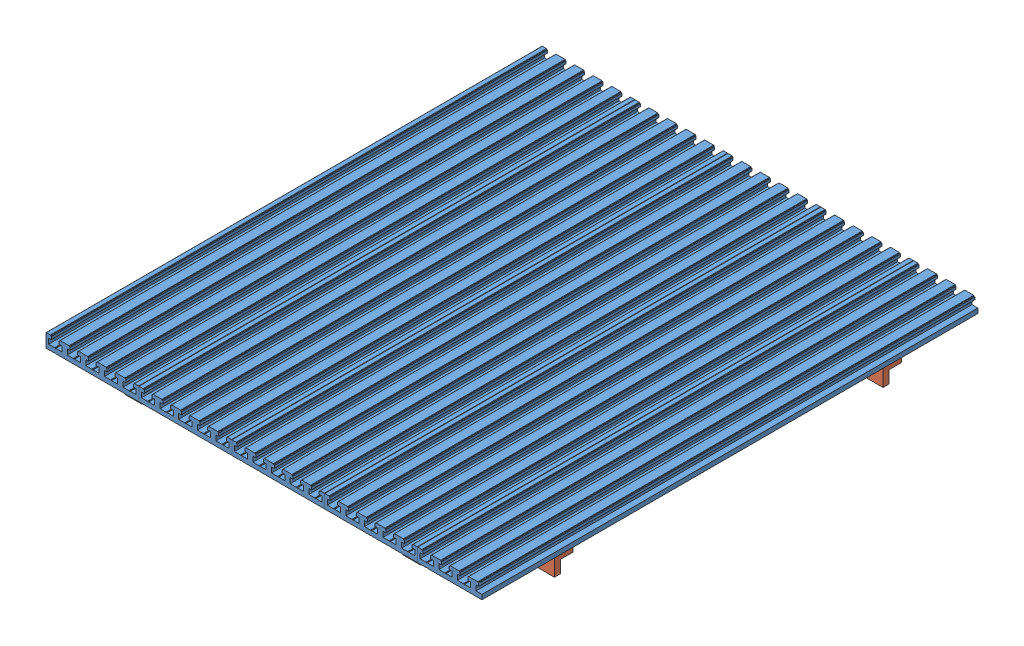
SolidWorks assembly TableTSlot, configuration Table T-Slot. Lengths in mm.
Overall size (351.6 29.5 400).
55 component instances, 6 part files, 100 mates.
Components (placement in the parent):
- T-slot Table Plate-4: T-slot Table Plate [-1 EdgeSide] at origin size (74.9 11 400)
- T-slot Table Plate-5: T-slot Table Plate [-2 Middle] at (74.9 0 0) size (74.9 11 400)
- T-slot Table Plate-6: T-slot Table Plate [-2 Middle] at (149.8 0 0) size (74.9 11 400)
- T-slot Table Plate-7: T-slot Table Plate [-1 EdgeSide] at (224.7 0 0) size (74.9 11 400)
- T-slot Table Plate-8: T-slot Table Plate [-3 aHalf] at (299.6 0 0) size (52 11 400)
- CornerBraketLong-1: CornerBraketLong [Corner Braket Long] at (312.55 -1.9 340) x (0 0 -1) z (-1 0 0) size (15 15 350)
- CornerBraketLong-2: CornerBraketLong [Corner Braket Long] at (312.55 -1.9 75) x (0 0 -1) z (-1 0 0) size (15 15 350)
- Corner Bracket 20х20L-1: Corner Bracket 20х20L [Default] at (23.5 -1.9 38.5) x (-1 0 0) z (0 0 1) size (17 18.5 18.5)
- Corner Bracket 20х20L-4: Corner Bracket 20х20L [Default] at (248.2 -1.9 38.5) x (-1 0 0) z (0 0 1) size (17 18.5 18.5)
- socket countersunk head screw_iso-1: socket countersunk head screw_iso [ISO 10642 - M3 x 16 - 16N] at (-30 1.76 65) x (0 -1 0) z (0.269005 0 -0.963139) size (16 5.54 5.54)
- socket countersunk head screw_iso-2: socket countersunk head screw_iso [ISO 10642 - M3 x 16 - 16N] at (30 1.76 65) x (0 -1 0) z (0.269005 0 -0.963139) size (16 5.54 5.54)
- socket countersunk head screw_iso-3: socket countersunk head screw_iso [ISO 10642 - M3 x 16 - 16N] at (44.9 1.76 65) x (0 -1 0) z (0.269005 0 -0.963139) size (16 5.54 5.54)
- socket countersunk head screw_iso-4: socket countersunk head screw_iso [ISO 10642 - M3 x 16 - 16N] at (104.9 1.76 65) x (0 -1 0) z (0.269005 0 -0.963139) size (16 5.54 5.54)
- socket countersunk head screw_iso-5: socket countersunk head screw_iso [ISO 10642 - M3 x 16 - 16N] at (119.8 1.76 65) x (0 -1 0) z (0.269005 0 -0.963139) size (16 5.54 5.54)
- socket countersunk head screw_iso-6: socket countersunk head screw_iso [ISO 10642 - M3 x 16 - 16N] at (179.8 1.76 65) x (0 -1 0) z (0.128637 0 -0.991692) size (16 5.54 5.54)
- socket countersunk head screw_iso-7: socket countersunk head screw_iso [ISO 10642 - M3 x 16 - 16N] at (194.7 1.76 65) x (0 -1 0) z (0.539742 0 -0.841831) size (16 5.54 5.54)
- socket countersunk head screw_iso-8: socket countersunk head screw_iso [ISO 10642 - M3 x 16 - 16N] at (254.7 1.76 65) x (0 -1 0) z (0.464702 0 -0.885467) size (16 5.54 5.54)
- socket countersunk head screw_iso-9: socket countersunk head screw_iso [ISO 10642 - M3 x 16 - 16N] at (254.7 1.76 330) x (0 -1 0) z (0.269005 0 -0.963139) size (16 5.54 5.54)
- socket countersunk head screw_iso-10: socket countersunk head screw_iso [ISO 10642 - M3 x 16 - 16N] at (194.7 1.76 330) x (0 -1 0) z (-0.059166 0 -0.998248) size (16 5.54 5.54)
- socket countersunk head screw_iso-11: socket countersunk head screw_iso [ISO 10642 - M3 x 16 - 16N] at (179.8 1.76 330) x (0 -1 0) z (0.269005 0 -0.963139) size (16 5.54 5.54)
- socket countersunk head screw_iso-12: socket countersunk head screw_iso [ISO 10642 - M3 x 16 - 16N] at (119.8 1.76 330) x (0 -1 0) z (0.269005 0 -0.963139) size (16 5.54 5.54)
- socket countersunk head screw_iso-13: socket countersunk head screw_iso [ISO 10642 - M3 x 16 - 16N] at (104.9 1.76 330) x (0 -1 0) z (0.048995 0 -0.998799) size (16 5.54 5.54)
- socket countersunk head screw_iso-14: socket countersunk head screw_iso [ISO 10642 - M3 x 16 - 16N] at (44.9 1.76 330) x (0 -1 0) z (0.269005 0 -0.963139) size (16 5.54 5.54)
- socket countersunk head screw_iso-15: socket countersunk head screw_iso [ISO 10642 - M3 x 16 - 16N] at (30 1.76 330) x (0 -1 0) z (0.351399 0 -0.936226) size (16 5.54 5.54)
- socket countersunk head screw_iso-16: socket countersunk head screw_iso [ISO 10642 - M3 x 16 - 16N] at (-30 1.76 330) x (0 -1 0) z (0.116212 0 -0.993224) size (16 5.54 5.54)
- socket head cap screw_iso-3: socket head cap screw_iso [ISO 4762 M4 x 6 - 6N] at (15 -8.4 30) x (0 1 0) z (0.250987 0 0.96799) size (10 7 7)
- socket head cap screw_iso-4: socket head cap screw_iso [ISO 4762 M4 x 6 - 6N] at (239.7 -8.4 30) x (0 1 0) z (0.250987 0 0.96799) size (10 7 7)
- Nyloc nut St_Steel A2 ISO M2_5-M36-1: Nyloc nut St_Steel A2 ISO M2_5-M36 [M3 NYLOC DIN 985] at (104.9 -6.9 65) x (0.275369 0 0.961338) z (0.961338 0 -0.275369) size (6.35 4 5.5)
- Nyloc nut St_Steel A2 ISO M2_5-M36-2: Nyloc nut St_Steel A2 ISO M2_5-M36 [M3 NYLOC DIN 985] at (119.8 -6.9 65) x (-0.786495 0 0.617596) z (0.617596 0 0.786495) size (6.35 4 5.5)
- Nyloc nut St_Steel A2 ISO M2_5-M36-3: Nyloc nut St_Steel A2 ISO M2_5-M36 [M3 NYLOC DIN 985] at (179.8 -6.9 65) x (-0.786495 0 0.617596) z (0.617596 0 0.786495) size (6.35 4 5.5)
- Nyloc nut St_Steel A2 ISO M2_5-M36-4: Nyloc nut St_Steel A2 ISO M2_5-M36 [M3 NYLOC DIN 985] at (194.7 -6.9 65) x (-0.786495 0 0.617596) z (0.617596 0 0.786495) size (6.35 4 5.5)
- Nyloc nut St_Steel A2 ISO M2_5-M36-5: Nyloc nut St_Steel A2 ISO M2_5-M36 [M3 NYLOC DIN 985] at (254.7 -6.9 65) x (-0.786495 0 0.617596) z (0.617596 0 0.786495) size (6.35 4 5.5)
- Nyloc nut St_Steel A2 ISO M2_5-M36-6: Nyloc nut St_Steel A2 ISO M2_5-M36 [M3 NYLOC DIN 985] at (44.9 -6.9 65) x (0.275369 0 0.961338) z (0.961338 0 -0.275369) size (6.35 4 5.5)
- Nyloc nut St_Steel A2 ISO M2_5-M36-7: Nyloc nut St_Steel A2 ISO M2_5-M36 [M3 NYLOC DIN 985] at (30 -6.9 65) x (0.275369 0 0.961338) z (0.961338 0 -0.275369) size (6.35 4 5.5)
- Nyloc nut St_Steel A2 ISO M2_5-M36-8: Nyloc nut St_Steel A2 ISO M2_5-M36 [M3 NYLOC DIN 985] at (-30 -6.9 65) x (0.275369 0 0.961338) z (0.961338 0 -0.275369) size (6.35 4 5.5)
- Nyloc nut St_Steel A2 ISO M2_5-M36-9: Nyloc nut St_Steel A2 ISO M2_5-M36 [M3 NYLOC DIN 985] at (-30 -6.9 330) x (0.275369 0 0.961338) z (0.961338 0 -0.275369) size (6.35 4 5.5)
- Nyloc nut St_Steel A2 ISO M2_5-M36-10: Nyloc nut St_Steel A2 ISO M2_5-M36 [M3 NYLOC DIN 985] at (30 -6.9 330) x (0.275369 0 0.961338) z (0.961338 0 -0.275369) size (6.35 4 5.5)
- Nyloc nut St_Steel A2 ISO M2_5-M36-11: Nyloc nut St_Steel A2 ISO M2_5-M36 [M3 NYLOC DIN 985] at (44.9 -6.9 330) x (0.275369 0 0.961338) z (0.961338 0 -0.275369) size (6.35 4 5.5)
- Nyloc nut St_Steel A2 ISO M2_5-M36-12: Nyloc nut St_Steel A2 ISO M2_5-M36 [M3 NYLOC DIN 985] at (104.9 -6.9 330) x (0.550614 0 0.83476) z (0.83476 0 -0.550614) size (6.35 4 5.5)
- Nyloc nut St_Steel A2 ISO M2_5-M36-13: Nyloc nut St_Steel A2 ISO M2_5-M36 [M3 NYLOC DIN 985] at (119.8 -6.9 330) x (0.275369 0 0.961338) z (0.961338 0 -0.275369) size (6.35 4 5.5)
- Nyloc nut St_Steel A2 ISO M2_5-M36-14: Nyloc nut St_Steel A2 ISO M2_5-M36 [M3 NYLOC DIN 985] at (179.8 -6.9 330) x (0.275369 0 0.961338) z (0.961338 0 -0.275369) size (6.35 4 5.5)
- Nyloc nut St_Steel A2 ISO M2_5-M36-15: Nyloc nut St_Steel A2 ISO M2_5-M36 [M3 NYLOC DIN 985] at (194.7 -6.9 330) x (0.275369 0 0.961338) z (0.961338 0 -0.275369) size (6.35 4 5.5)
- Nyloc nut St_Steel A2 ISO M2_5-M36-16: Nyloc nut St_Steel A2 ISO M2_5-M36 [M3 NYLOC DIN 985] at (254.7 -6.9 330) x (0.275369 0 0.961338) z (0.961338 0 -0.275369) size (6.35 4 5.5)
- socket countersunk head screw_iso-17: socket countersunk head screw_iso [ISO 10642 - M3 x 16 - 16N] at (269.6 1.76 330) x (0 -1 0) z (0.057721 0 -0.998333) size (16 5.54 5.54)
- socket countersunk head screw_iso-18: socket countersunk head screw_iso [ISO 10642 - M3 x 16 - 16N] at (299.6 1.76 330) x (0 -1 0) z (0.057721 0 -0.998333) size (16 5.54 5.54)
- socket countersunk head screw_iso-19: socket countersunk head screw_iso [ISO 10642 - M3 x 16 - 16N] at (269.6 1.76 65) x (0 -1 0) z (0.464702 0 -0.885467) size (16 5.54 5.54)
- socket countersunk head screw_iso-20: socket countersunk head screw_iso [ISO 10642 - M3 x 16 - 16N] at (299.6 1.76 65) x (0 -1 0) z (0.464702 0 -0.885467) size (16 5.54 5.54)
- Nyloc nut St_Steel A2 ISO M2_5-M36-17: Nyloc nut St_Steel A2 ISO M2_5-M36 [M3 NYLOC DIN 985] at (269.6 -6.9 65) x (-0.786495 0 0.617596) z (0.617596 0 0.786495) size (6.35 4 5.5)
- Nyloc nut St_Steel A2 ISO M2_5-M36-18: Nyloc nut St_Steel A2 ISO M2_5-M36 [M3 NYLOC DIN 985] at (299.6 -6.9 65) x (-0.786495 0 0.617596) z (0.617596 0 0.786495) size (6.35 4 5.5)
- Nyloc nut St_Steel A2 ISO M2_5-M36-19: Nyloc nut St_Steel A2 ISO M2_5-M36 [M3 NYLOC DIN 985] at (269.6 -6.9 330) x (0.275369 0 0.961338) z (0.961338 0 -0.275369) size (6.35 4 5.5)
- Nyloc nut St_Steel A2 ISO M2_5-M36-20: Nyloc nut St_Steel A2 ISO M2_5-M36 [M3 NYLOC DIN 985] at (299.6 -6.9 330) x (0.275369 0 0.961338) z (0.961338 0 -0.275369) size (6.35 4 5.5)
- socket head cap screw_iso-5: socket head cap screw_iso [ISO 4762 M4 x 6 - 6N] at (15 -8.4 372) x (0 1 0) z (0.500858 0 0.86553) size (10 7 7)
- socket head cap screw_iso-6: socket head cap screw_iso [ISO 4762 M4 x 6 - 6N] at (239.7 -8.4 372) x (0 1 0) z (0.500858 0 0.86553) size (10 7 7)
- Corner Bracket 20х20L-6: Corner Bracket 20х20L [Default] at (231.2 -1.9 363.5) x (1 0 0) z (0 0 -1) size (17 18.5 18.5)
- Corner Bracket 20х20L-5: Corner Bracket 20х20L [Default] at (6.5 -1.9 363.5) x (1 0 0) z (0 0 -1) size (17 18.5 18.5)
Mates (geometry in assembly coordinates):
- Coincident1: coincident aligned: plane of T-slot Table Plate-4 through (37.2 8.85 0) normal (0 0 -1); plane of T-slot Table Plate-5 through (112.1 8.85 0) normal (0 0 -1)
- Coincident2: coincident aligned: plane of T-slot Table Plate-5 through (112.1 8.85 0) normal (0 0 -1); plane of T-slot Table Plate-6 through (187 8.85 0) normal (0 0 -1)
- Coincident3: coincident aligned: plane of T-slot Table Plate-5 through (112.1 -1.9 400) normal (0 -1 0); plane of T-slot Table Plate-6 through (134.2564 -1.9 400) normal (0 -1 0)
- Coincident4: coincident aligned: plane of T-slot Table Plate-4 through (37.2 -1.9 400) normal (0 -1 0); plane of T-slot Table Plate-5 through (59.3564 -1.9 400) normal (0 -1 0)
- Coincident5: coincident anti-aligned: plane of T-slot Table Plate-4 through (37.45 8.85 400) normal (1 0 0); plane of T-slot Table Plate-5 through (37.45 -1.65 400) normal (-1 0 0)
- Coincident6: coincident anti-aligned: plane of T-slot Table Plate-5 through (112.35 8.85 400) normal (1 0 0); plane of T-slot Table Plate-6 through (112.35 -1.65 400) normal (-1 0 0)
- Coincident7: coincident aligned: plane of T-slot Table Plate-6 through (187 8.85 0) normal (0 0 -1); plane of T-slot Table Plate-7 through (261.9 8.85 0) normal (0 0 -1)
- Coincident8: coincident aligned: plane of T-slot Table Plate-6 through (187 -1.9 400) normal (0 -1 0); plane of T-slot Table Plate-7 through (194.1564 -1.9 400) normal (0 -1 0)
- Coincident9: coincident anti-aligned: plane of T-slot Table Plate-6 through (187.25 8.85 400) normal (1 0 0); plane of T-slot Table Plate-7 through (187.25 -1.65 400) normal (-1 0 0)
- Coincident10: coincident anti-aligned: plane of T-slot Table Plate-4 through (14.4564 -1.9 400) normal (0 -1 0); plane of Corner Bracket 20х20L-1 through (6.5 -1.9 24.5) normal (0 1 0)
- Coincident11: coincident anti-aligned: plane of T-slot Table Plate-4 through (-15.5436 -1.9 400) normal (0 -1 0); plane of CornerBraketLong^TableTSlot_cnc_laser_v1.0-1 through (-37.45 -1.9 325) normal (0 1 0)
- Coincident12: coincident anti-aligned: plane of T-slot Table Plate-6 through (179.2564 -1.9 400) normal (0 -1 0); plane of CornerBraketLong^TableTSlot_cnc_laser_v1.0-2 through (-37.45 -1.9 60) normal (0 1 0)
- Coincident19: coincident anti-aligned: plane of T-slot Table Plate-5 through (74.3564 -1.9 400) normal (0 -1 0); plane of Corner Bracket 20х20L-4 through (231.2 -1.9 24.5) normal (0 1 0)
- Coincident20: coincident aligned: plane of Corner Bracket 20х20L-1 through (6.5 -20.4 20) normal (0 0 -1); plane of Corner Bracket 20х20L-4 through (231.2 -20.4 20) normal (0 0 -1)
- Concentric1: concentric aligned: cylinder of socket countersunk head screw_iso-1 through (-30 1.76 65) axis (0 1 0) radius 1.5; cylinder of CornerBraketLong^TableTSlot_cnc_laser_v1.0-2 through (-30 -1.9 65) axis (0 1 0) radius 1.6
- Coincident27: coincident aligned: cone of T-slot Table Plate-4 through (-30 1.4 65) axis (0 -1 0); cylinder of socket countersunk head screw_iso-1 through (-30 1.17 65) axis (0 -1 0) radius 785.3982
- Concentric4: concentric aligned: cylinder of CornerBraketLong^TableTSlot_cnc_laser_v1.0-1 through (-30 -1.9 330) axis (0 1 0) radius 1.6; cylinder of T-slot Table Plate-4 through (-30 1.9 330) axis (0 1 0) radius 1.6
- Concentric17: concentric aligned: cylinder of socket countersunk head screw_iso-14 through (44.9 1.76 330) axis (0 1 0) radius 1.5; cylinder of CornerBraketLong^TableTSlot_cnc_laser_v1.0-1 through (44.9 -1.9 330) axis (0 1 0) radius 1.6
- Concentric18: concentric aligned: cylinder of socket countersunk head screw_iso-15 through (30 1.76 330) axis (0 1 0) radius 1.5; cylinder of CornerBraketLong^TableTSlot_cnc_laser_v1.0-1 through (30 -1.9 330) axis (0 1 0) radius 1.6
- Concentric19: concentric aligned: cylinder of socket countersunk head screw_iso-16 through (-30 1.76 330) axis (0 1 0) radius 1.5; cylinder of T-slot Table Plate-4 through (-30 1.9 330) axis (0 1 0) radius 1.6
- Coincident36: coincident aligned: cylinder of T-slot Table Plate-4 through (-30 1.4 330) axis (0 -1 0) radius 785.3982; cylinder of socket countersunk head screw_iso-16 through (-30 1.17 330) axis (0 -1 0) radius 785.3982
- Coincident37: coincident aligned: cylinder of T-slot Table Plate-4 through (30 1.4 330) axis (0 -1 0) radius 785.3982; cylinder of socket countersunk head screw_iso-15 through (30 1.17 330) axis (0 -1 0) radius 785.3982
- Coincident38: coincident aligned: cylinder of T-slot Table Plate-5 through (44.9 1.4 330) axis (0 -1 0) radius 785.3982; cylinder of socket countersunk head screw_iso-14 through (44.9 1.17 330) axis (0 -1 0) radius 785.3982
- Coincident39: coincident aligned: cylinder of T-slot Table Plate-5 through (104.9 1.4 330) axis (0 -1 0) radius 785.3982; cylinder of socket countersunk head screw_iso-13 through (104.9 1.17 330) axis (0 -1 0) radius 785.3982
- Coincident40: coincident aligned: cylinder of T-slot Table Plate-6 through (119.8 1.4 330) axis (0 -1 0) radius 785.3982; cylinder of socket countersunk head screw_iso-12 through (119.8 1.17 330) axis (0 -1 0) radius 785.3982
- Coincident41: coincident aligned: cylinder of T-slot Table Plate-6 through (179.8 1.4 330) axis (0 -1 0) radius 785.3982; cylinder of socket countersunk head screw_iso-11 through (179.8 1.17 330) axis (0 -1 0) radius 785.3982
- Coincident42: coincident aligned: cylinder of T-slot Table Plate-7 through (194.7 1.4 330) axis (0 -1 0) radius 785.3982; cylinder of socket countersunk head screw_iso-10 through (194.7 1.17 330) axis (0 -1 0) radius 785.3982
- Coincident43: coincident aligned: cylinder of T-slot Table Plate-7 through (254.7 1.4 330) axis (0 -1 0) radius 785.3982; cylinder of socket countersunk head screw_iso-9 through (254.7 1.17 330) axis (0 -1 0) radius 785.3982
- Concentric30: concentric aligned: cylinder of T-slot Table Plate-4 through (15 1.9 30) axis (0 1 0) radius 1.65; cylinder of Corner Bracket 20х20L-1 through (15 -18.9 30) axis (0 1 0) radius 2.55
- Concentric32: concentric anti-aligned: cylinder of T-slot Table Plate-4 through (15 1.9 30) axis (0 1 0) radius 1.65; cylinder of socket head cap screw_iso-3 through (15 -40.15 30) axis (0 -1 0) radius 2
- Coincident51: coincident anti-aligned: plane of Corner Bracket 20х20L-1 through (6.5 -4.4 24.5) normal (0 -1 0); plane of socket head cap screw_iso-3 through (11.612 -4.4 30.8785) normal (0 1 0)
- Concentric33: concentric aligned: cylinder of Corner Bracket 20х20L-4 through (239.7 -18.9 30) axis (0 1 0) radius 2.55; cylinder of T-slot Table Plate-7 through (239.7 1.9 30) axis (0 1 0) radius 1.65
- Concentric34: concentric anti-aligned: cylinder of Corner Bracket 20х20L-4 through (239.7 -18.9 30) axis (0 1 0) radius 2.55; cylinder of socket head cap screw_iso-4 through (239.7 -40.15 30) axis (0 -1 0) radius 2
- Coincident54: coincident anti-aligned: plane of Corner Bracket 20х20L-4 through (231.2 -4.4 24.5) normal (0 -1 0); plane of socket head cap screw_iso-4 through (236.312 -4.4 30.8785) normal (0 1 0)
- Concentric35: concentric aligned: cylinder of CornerBraketLong^TableTSlot_cnc_laser_v1.0-2 through (-30 -1.9 65) axis (0 1 0) radius 1.6; cylinder of socket countersunk head screw_iso-1 through (-30 1.76 65) axis (0 1 0) radius 1.5
- Coincident55: coincident anti-aligned: plane of CornerBraketLong^TableTSlot_cnc_laser_v1.0-2 through (-37.45 -1.9 60) normal (0 1 0); plane of T-slot Table Plate-8 through (284.0564 -1.9 400) normal (0 -1 0)
- Coincident56: coincident aligned: plane of T-slot Table Plate-7 through (261.9 8.85 0) normal (0 0 -1); plane of T-slot Table Plate-8 through (336.8 8.85 0) normal (0 0 -1)
- Coincident57: coincident anti-aligned: plane of T-slot Table Plate-7 through (262.15 8.85 400) normal (1 0 0); plane of T-slot Table Plate-8 through (262.15 -1.65 400) normal (-1 0 0)
- Concentric36: concentric anti-aligned: cylinder of socket countersunk head screw_iso-4 through (104.9 1.76 65) axis (0 1 0) radius 1.5; cylinder of Nyloc nut St_Steel A2 ISO M2_5-M36-1 through (104.9 -6.9 65) axis (0 -1 0) radius 1.195
- Coincident58: coincident anti-aligned: plane of CornerBraketLong^TableTSlot_cnc_laser_v1.0-2 through (-37.45 -6.9 70) normal (0 -1 0); plane of Nyloc nut St_Steel A2 ISO M2_5-M36-1 through (105.7744 -6.9 68.0527) normal (0 1 0)
- Concentric371: concentric aligned: cylinder of socket countersunk head screw_iso-5 through (119.8 1.76 65) axis (0 1 0) radius 1.5; cylinder of Nyloc nut St_Steel A2 ISO M2_5-M36-2 through (119.8 -10.9 65) axis (0 1 0) radius 2.75
- Coincident59: coincident anti-aligned: plane of CornerBraketLong^TableTSlot_cnc_laser_v1.0-2 through (-37.45 -6.9 70) normal (0 -1 0); plane of Nyloc nut St_Steel A2 ISO M2_5-M36-2 through (117.3025 -6.9 66.9611) normal (0 1 0)
- Concentric381: concentric aligned: cylinder of CornerBraketLong^TableTSlot_cnc_laser_v1.0-2 through (179.8 -1.9 65) axis (0 1 0) radius 1.6; cylinder of Nyloc nut St_Steel A2 ISO M2_5-M36-3 through (179.8 -6.9 65) axis (0 1 0) radius 1047.1976
- Coincident601: coincident anti-aligned: plane of CornerBraketLong^TableTSlot_cnc_laser_v1.0-2 through (-37.45 -6.9 70) normal (0 -1 0); plane of Nyloc nut St_Steel A2 ISO M2_5-M36-3 through (177.3025 -6.9 66.9611) normal (0 1 0)
- Concentric391: concentric aligned: cylinder of CornerBraketLong^TableTSlot_cnc_laser_v1.0-2 through (194.7 -1.9 65) axis (0 1 0) radius 1.6; cylinder of Nyloc nut St_Steel A2 ISO M2_5-M36-4 through (194.7 -6.9 65) axis (0 1 0) radius 1047.1976
- Coincident611: coincident anti-aligned: plane of CornerBraketLong^TableTSlot_cnc_laser_v1.0-2 through (-37.45 -6.9 70) normal (0 -1 0); plane of Nyloc nut St_Steel A2 ISO M2_5-M36-4 through (192.2025 -6.9 66.9611) normal (0 1 0)
- Concentric401: concentric aligned: cylinder of CornerBraketLong^TableTSlot_cnc_laser_v1.0-2 through (254.7 -1.9 65) axis (0 1 0) radius 1.6; cylinder of Nyloc nut St_Steel A2 ISO M2_5-M36-5 through (254.7 -6.9 65) axis (0 1 0) radius 1047.1976
- Coincident621: coincident anti-aligned: plane of CornerBraketLong^TableTSlot_cnc_laser_v1.0-2 through (-37.45 -6.9 70) normal (0 -1 0); plane of Nyloc nut St_Steel A2 ISO M2_5-M36-5 through (252.2025 -6.9 66.9611) normal (0 1 0)
- Concentric411: concentric aligned: cylinder of CornerBraketLong^TableTSlot_cnc_laser_v1.0-2 through (44.9 -1.9 65) axis (0 1 0) radius 1.6; cylinder of Nyloc nut St_Steel A2 ISO M2_5-M36-6 through (44.9 -6.9 65) axis (0 1 0) radius 1047.1976
- Coincident631: coincident anti-aligned: plane of CornerBraketLong^TableTSlot_cnc_laser_v1.0-2 through (-37.45 -6.9 70) normal (0 -1 0); plane of Nyloc nut St_Steel A2 ISO M2_5-M36-6 through (45.7744 -6.9 68.0527) normal (0 1 0)
- Concentric421: concentric aligned: cylinder of CornerBraketLong^TableTSlot_cnc_laser_v1.0-2 through (30 -1.9 65) axis (0 1 0) radius 1.6; cylinder of Nyloc nut St_Steel A2 ISO M2_5-M36-7 through (30 -6.9 65) axis (0 1 0) radius 1047.1976
- Coincident641: coincident anti-aligned: plane of CornerBraketLong^TableTSlot_cnc_laser_v1.0-2 through (-37.45 -6.9 70) normal (0 -1 0); plane of Nyloc nut St_Steel A2 ISO M2_5-M36-7 through (30.8744 -6.9 68.0527) normal (0 1 0)
- Concentric431: concentric aligned: cylinder of CornerBraketLong^TableTSlot_cnc_laser_v1.0-2 through (-30 -1.9 65) axis (0 1 0) radius 1.6; cylinder of Nyloc nut St_Steel A2 ISO M2_5-M36-8 through (-30 -6.9 65) axis (0 1 0) radius 1047.1976
- Coincident651: coincident anti-aligned: plane of CornerBraketLong^TableTSlot_cnc_laser_v1.0-2 through (-37.45 -6.9 70) normal (0 -1 0); plane of Nyloc nut St_Steel A2 ISO M2_5-M36-8 through (-29.1256 -6.9 68.0527) normal (0 1 0)
- Concentric44: concentric aligned: cylinder of CornerBraketLong^TableTSlot_cnc_laser_v1.0-2 through (254.7 -1.9 65) axis (0 1 0) radius 1.6; cylinder of socket countersunk head screw_iso-8 through (254.7 1.76 65) axis (0 1 0) radius 1.5
- Coincident66: coincident anti-aligned: plane of CornerBraketLong^TableTSlot_cnc_laser_v1.0-1 through (-37.45 -6.9 335) normal (0 -1 0); plane of Nyloc nut St_Steel A2 ISO M2_5-M36-9 through (-29.1256 -6.9 333.0526) normal (0 1 0)
- Concentric45: concentric anti-aligned: cylinder of socket countersunk head screw_iso-16 through (-30 1.76 330) axis (0 1 0) radius 1.5; cylinder of Nyloc nut St_Steel A2 ISO M2_5-M36-9 through (-30 -6.9 330) axis (0 -1 0) radius 1.195
- Concentric461: concentric aligned: cylinder of CornerBraketLong^TableTSlot_cnc_laser_v1.0-1 through (30 -1.9 330) axis (0 1 0) radius 1.6; cylinder of Nyloc nut St_Steel A2 ISO M2_5-M36-10 through (30 -6.9 330) axis (0 1 0) radius 1047.1976
- Coincident671: coincident anti-aligned: plane of CornerBraketLong^TableTSlot_cnc_laser_v1.0-1 through (-37.45 -6.9 335) normal (0 -1 0); plane of Nyloc nut St_Steel A2 ISO M2_5-M36-10 through (30.8744 -6.9 333.0526) normal (0 1 0)
- Concentric471: concentric aligned: cylinder of CornerBraketLong^TableTSlot_cnc_laser_v1.0-1 through (44.9 -1.9 330) axis (0 1 0) radius 1.6; cylinder of Nyloc nut St_Steel A2 ISO M2_5-M36-11 through (44.9 -6.9 330) axis (0 1 0) radius 1047.1976
- Coincident681: coincident anti-aligned: plane of CornerBraketLong^TableTSlot_cnc_laser_v1.0-1 through (-37.45 -6.9 335) normal (0 -1 0); plane of Nyloc nut St_Steel A2 ISO M2_5-M36-11 through (45.7744 -6.9 333.0526) normal (0 1 0)
- Concentric481: concentric aligned: cylinder of CornerBraketLong^TableTSlot_cnc_laser_v1.0-1 through (104.9 -1.9 330) axis (0 1 0) radius 1.6; cylinder of Nyloc nut St_Steel A2 ISO M2_5-M36-12 through (104.9 -6.9 330) axis (0 1 0) radius 1047.1976
- Coincident691: coincident anti-aligned: plane of CornerBraketLong^TableTSlot_cnc_laser_v1.0-1 through (-37.45 -6.9 335) normal (0 -1 0); plane of Nyloc nut St_Steel A2 ISO M2_5-M36-12 through (106.6484 -6.9 332.6507) normal (0 1 0)
- Concentric491: concentric aligned: cylinder of CornerBraketLong^TableTSlot_cnc_laser_v1.0-1 through (119.8 -1.9 330) axis (0 1 0) radius 1.6; cylinder of Nyloc nut St_Steel A2 ISO M2_5-M36-13 through (119.8 -6.9 330) axis (0 1 0) radius 1047.1976
- Coincident701: coincident anti-aligned: plane of CornerBraketLong^TableTSlot_cnc_laser_v1.0-1 through (-37.45 -6.9 335) normal (0 -1 0); plane of Nyloc nut St_Steel A2 ISO M2_5-M36-13 through (120.6744 -6.9 333.0526) normal (0 1 0)
- Concentric501: concentric aligned: cylinder of CornerBraketLong^TableTSlot_cnc_laser_v1.0-1 through (179.8 -1.9 330) axis (0 1 0) radius 1.6; cylinder of Nyloc nut St_Steel A2 ISO M2_5-M36-14 through (179.8 -6.9 330) axis (0 1 0) radius 1047.1976
- Coincident711: coincident anti-aligned: plane of CornerBraketLong^TableTSlot_cnc_laser_v1.0-1 through (-37.45 -6.9 335) normal (0 -1 0); plane of Nyloc nut St_Steel A2 ISO M2_5-M36-14 through (180.6744 -6.9 333.0526) normal (0 1 0)
- Concentric511: concentric aligned: cylinder of CornerBraketLong^TableTSlot_cnc_laser_v1.0-1 through (194.7 -1.9 330) axis (0 1 0) radius 1.6; cylinder of Nyloc nut St_Steel A2 ISO M2_5-M36-15 through (194.7 -6.9 330) axis (0 1 0) radius 1047.1976
- Coincident721: coincident anti-aligned: plane of CornerBraketLong^TableTSlot_cnc_laser_v1.0-1 through (-37.45 -6.9 335) normal (0 -1 0); plane of Nyloc nut St_Steel A2 ISO M2_5-M36-15 through (195.5744 -6.9 333.0526) normal (0 1 0)
- Concentric521: concentric aligned: cylinder of CornerBraketLong^TableTSlot_cnc_laser_v1.0-1 through (254.7 -1.9 330) axis (0 1 0) radius 1.6; cylinder of Nyloc nut St_Steel A2 ISO M2_5-M36-16 through (254.7 -6.9 330) axis (0 1 0) radius 1047.1976
- Coincident731: coincident anti-aligned: plane of CornerBraketLong^TableTSlot_cnc_laser_v1.0-1 through (-37.45 -6.9 335) normal (0 -1 0); plane of Nyloc nut St_Steel A2 ISO M2_5-M36-16 through (255.5744 -6.9 333.0526) normal (0 1 0)
- Coincident741: coincident aligned: cylinder of T-slot Table Plate-8 through (269.6 1.4 330) axis (0 -1 0) radius 785.3982; cylinder of socket countersunk head screw_iso-17 through (269.6 1.17 330) axis (0 -1 0) radius 785.3982
- Coincident751: coincident aligned: cylinder of T-slot Table Plate-8 through (299.6 1.4 330) axis (0 -1 0) radius 785.3982; cylinder of socket countersunk head screw_iso-18 through (299.6 1.17 330) axis (0 -1 0) radius 785.3982
- Coincident761: coincident aligned: cylinder of T-slot Table Plate-8 through (269.6 1.4 65) axis (0 -1 0) radius 785.3982; cylinder of socket countersunk head screw_iso-19 through (269.6 1.17 65) axis (0 -1 0) radius 785.3982
- Coincident771: coincident aligned: cylinder of T-slot Table Plate-8 through (299.6 1.4 65) axis (0 -1 0) radius 785.3982; cylinder of socket countersunk head screw_iso-20 through (299.6 1.17 65) axis (0 -1 0) radius 785.3982
- Concentric531: concentric aligned: cylinder of CornerBraketLong^TableTSlot_cnc_laser_v1.0-2 through (269.6 -1.9 65) axis (0 1 0) radius 1.6; cylinder of Nyloc nut St_Steel A2 ISO M2_5-M36-17 through (269.6 -6.9 65) axis (0 1 0) radius 1047.1976
- Coincident781: coincident anti-aligned: plane of CornerBraketLong^TableTSlot_cnc_laser_v1.0-2 through (-37.45 -6.9 70) normal (0 -1 0); plane of Nyloc nut St_Steel A2 ISO M2_5-M36-17 through (267.1025 -6.9 66.9611) normal (0 1 0)
- Concentric541: concentric aligned: cylinder of CornerBraketLong^TableTSlot_cnc_laser_v1.0-2 through (299.6 -1.9 65) axis (0 1 0) radius 1.6; cylinder of Nyloc nut St_Steel A2 ISO M2_5-M36-18 through (299.6 -6.9 65) axis (0 1 0) radius 1047.1976
- Coincident791: coincident anti-aligned: plane of CornerBraketLong^TableTSlot_cnc_laser_v1.0-2 through (-37.45 -6.9 70) normal (0 -1 0); plane of Nyloc nut St_Steel A2 ISO M2_5-M36-18 through (297.1025 -6.9 66.9611) normal (0 1 0)
- Concentric551: concentric aligned: cylinder of CornerBraketLong^TableTSlot_cnc_laser_v1.0-1 through (269.6 -1.9 330) axis (0 1 0) radius 1.6; cylinder of Nyloc nut St_Steel A2 ISO M2_5-M36-19 through (269.6 -6.9 330) axis (0 1 0) radius 1047.1976
- Coincident801: coincident anti-aligned: plane of CornerBraketLong^TableTSlot_cnc_laser_v1.0-1 through (-37.45 -6.9 335) normal (0 -1 0); plane of Nyloc nut St_Steel A2 ISO M2_5-M36-19 through (270.4744 -6.9 333.0526) normal (0 1 0)
- Concentric56: concentric aligned: cylinder of CornerBraketLong^TableTSlot_cnc_laser_v1.0-1 through (299.6 -1.9 330) axis (0 1 0) radius 1.6; cylinder of socket countersunk head screw_iso-18 through (299.6 1.76 330) axis (0 1 0) radius 1.5
- Concentric571: concentric aligned: cylinder of CornerBraketLong^TableTSlot_cnc_laser_v1.0-1 through (299.6 -1.9 330) axis (0 1 0) radius 1.6; cylinder of Nyloc nut St_Steel A2 ISO M2_5-M36-20 through (299.6 -6.9 330) axis (0 1 0) radius 1047.1976
- Coincident811: coincident anti-aligned: plane of CornerBraketLong^TableTSlot_cnc_laser_v1.0-1 through (-37.45 -6.9 335) normal (0 -1 0); plane of Nyloc nut St_Steel A2 ISO M2_5-M36-20 through (300.4744 -6.9 333.0526) normal (0 1 0)
- Coincident812: coincident anti-aligned: plane of Corner Bracket 20х20L-5 through (23.5 -4.4 377.5) normal (0 -1 0); plane of socket head cap screw_iso-5 through (11.9706 -4.4 373.753) normal (0 1 0)
- Concentric572: concentric anti-aligned: cylinder of Corner Bracket 20х20L-5 through (15 -18.9 372) axis (0 1 0) radius 2.55; cylinder of socket head cap screw_iso-5 through (15 -40.15 372) axis (0 -1 0) radius 2
- Coincident814: coincident anti-aligned: plane of T-slot Table Plate-4 through (14.4564 -1.9 400) normal (0 -1 0); plane of Corner Bracket 20х20L-5 through (23.5 -1.9 377.5) normal (0 1 0)
- Concentric575: concentric anti-aligned: cylinder of T-slot Table Plate-4 through (15 1.9 372) axis (0 1 0) radius 1.65; cylinder of socket head cap screw_iso-5 through (15 -40.15 372) axis (0 -1 0) radius 3.5
- Parallel2: parallel aligned: plane of T-slot Table Plate-4 through (37.2 8.85 400) normal (0 0 1); plane of Corner Bracket 20х20L-5 through (23.5 -20.4 382) normal (0 0 1)
- Coincident815: coincident anti-aligned: plane of socket head cap screw_iso-6 through (236.6706 -4.4 373.753) normal (0 1 0); plane of Corner Bracket 20х20L-6 through (248.2 -4.4 377.5) normal (0 -1 0)
- Concentric576: concentric anti-aligned: cylinder of socket head cap screw_iso-6 through (239.7 -40.15 372) axis (0 -1 0) radius 2; cylinder of Corner Bracket 20х20L-6 through (239.7 -18.9 372) axis (0 1 0) radius 2.55
- Coincident817: coincident anti-aligned: plane of T-slot Table Plate-7 through (254.1564 -1.9 400) normal (0 -1 0); plane of Corner Bracket 20х20L-6 through (248.2 -1.9 377.5) normal (0 1 0)
- Concentric579: concentric anti-aligned: cylinder of T-slot Table Plate-7 through (239.7 1.9 372) axis (0 1 0) radius 1.65; cylinder of socket head cap screw_iso-6 through (239.7 -40.15 372) axis (0 -1 0) radius 2
- Coincident818: coincident aligned: cylinder of T-slot Table Plate-7 through (254.7 1.4 65) axis (0 -1 0) radius 785.3982; cylinder of socket countersunk head screw_iso-8 through (254.7 1.17 65) axis (0 -1 0) radius 785.3982
- Coincident819: coincident aligned: cylinder of T-slot Table Plate-7 through (194.7 1.4 65) axis (0 -1 0) radius 785.3982; cylinder of socket countersunk head screw_iso-7 through (194.7 1.17 65) axis (0 -1 0) radius 785.3982
- Coincident820: coincident aligned: cylinder of T-slot Table Plate-6 through (179.8 1.4 65) axis (0 -1 0) radius 785.3982; cylinder of socket countersunk head screw_iso-6 through (179.8 1.17 65) axis (0 -1 0) radius 785.3982
- Coincident821: coincident aligned: cylinder of T-slot Table Plate-6 through (119.8 1.4 65) axis (0 -1 0) radius 785.3982; cylinder of socket countersunk head screw_iso-5 through (119.8 1.17 65) axis (0 -1 0) radius 785.3982
- Coincident822: coincident aligned: cylinder of T-slot Table Plate-5 through (104.9 1.4 65) axis (0 -1 0) radius 785.3982; cylinder of socket countersunk head screw_iso-4 through (104.9 1.17 65) axis (0 -1 0) radius 785.3982
- Coincident823: coincident aligned: cylinder of T-slot Table Plate-5 through (44.9 1.4 65) axis (0 -1 0) radius 785.3982; cylinder of socket countersunk head screw_iso-3 through (44.9 1.17 65) axis (0 -1 0) radius 785.3982
- Coincident824: coincident aligned: cylinder of T-slot Table Plate-4 through (30 1.4 65) axis (0 -1 0) radius 785.3982; cylinder of socket countersunk head screw_iso-2 through (30 1.17 65) axis (0 -1 0) radius 785.3982
